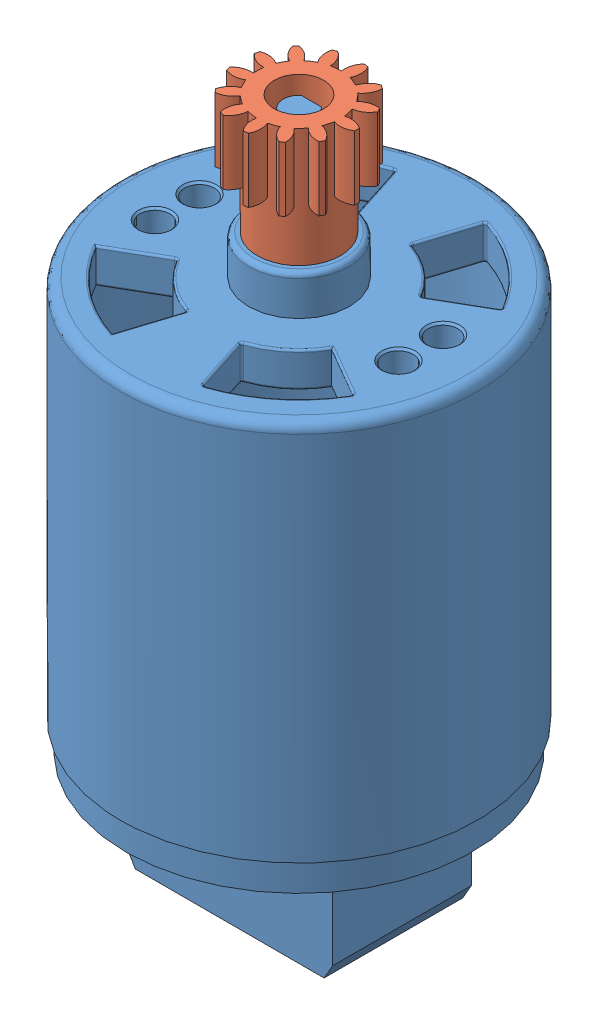
SolidWorks assembly MotorEngrane, configuration Predeterminado. Lengths in mm.
Overall size (36 69.5 36).
2 component instances, 2 part files, 2 mates.
Components (placement in the parent):
- Motor-1: Motor [Default] at (-5.1493 -20.5161 68.3) size (36 68.3 36)
- Gear 13T-1: Gear 13T [Default] at (-5.1493 27.4839 68.3) x (0 1 0) z (-0.927124 0 -0.374755) size (12 11.88 11.96)
Mates (geometry in assembly coordinates):
- Concéntrica1: concentric: cylinder of Motor-1 through (-5.1493 32.7839 68.3) axis (0 -1 0) radius 1.6; cylinder of Gear 13T-1 through (-5.1493 39.484 68.3) axis (0 -1 0) radius 2.5
- Coincidente2: coincident: plane of Motor-1 through (-5.1493 21.9839 68.3) normal (0 1 0); plane of Gear 13T-1 through (-5.1493 21.9839 68.3) normal (0 -1 0)
